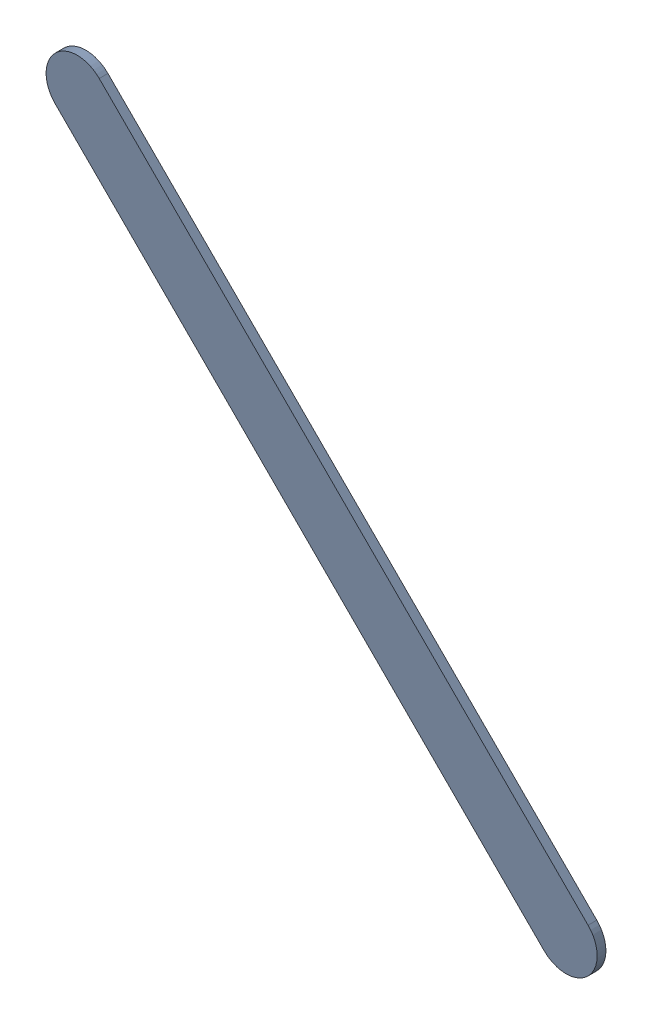
SolidWorks assembly Track (17.308mm,50.7mm)(19.304mm,48.704mm) on Bottom Layer, configuration Predeterminado. Lengths in mm.
Overall size (2.25 2.25 0.04).
2 component instances, 1 part files, 0 mates.
Components (placement in the parent):
- Track (17.308mm,50.7mm)(19.304mm,48.704mm) on Bottom Layer-1-1: Track (17.308mm,50.7mm)(19.304mm,48.704mm) on Bottom Layer-1 [Predeterminado] at (-68.317 -44.187 -0.4013) size (2.25 2.25 0.04)
  - Track (17.308mm,50.7mm)(19.304mm,48.704mm) on Bottom Layer-Part-1-1: Track (17.308mm,50.7mm)(19.304mm,48.704mm) on Bottom Layer-Part-1 [Predeterminado] at origin size (2.25 2.25 0.04)
